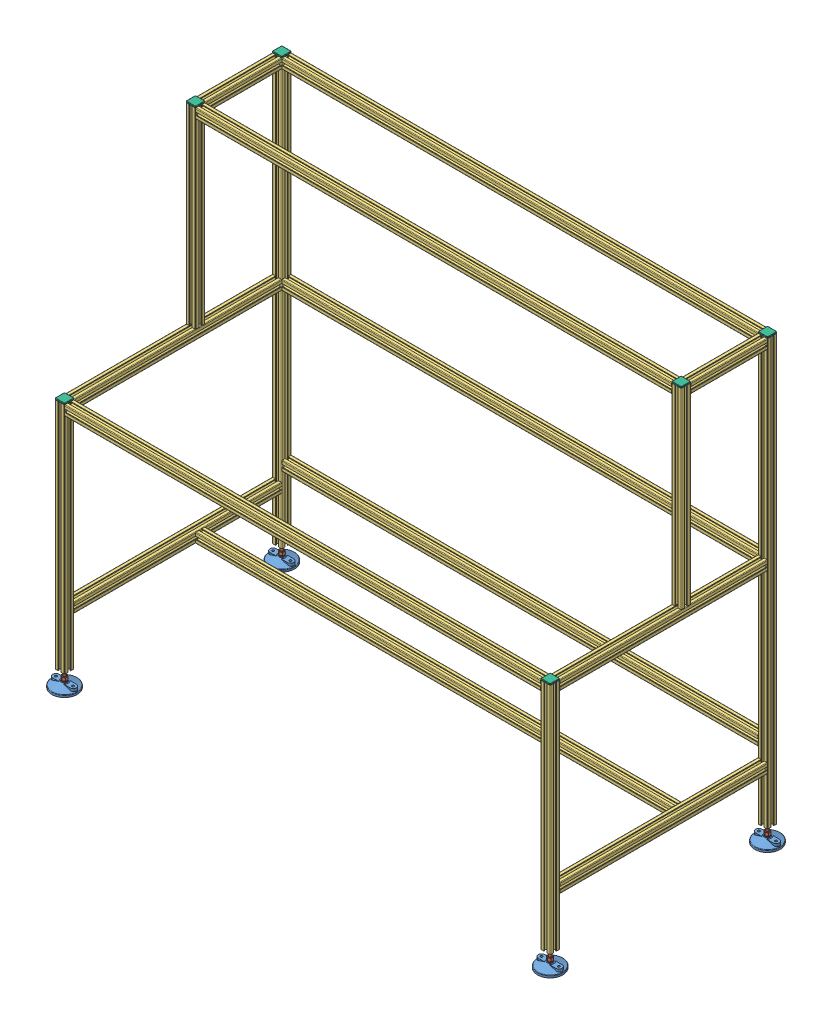
SolidWorks assembly AL-6 Рабочий стол большой с одной полкой сборка, configuration По умолчанию. Lengths in mm.
Overall size (1599 1384.2 759).
63 component instances, 6 part files, 70 mates.
Components (placement in the parent):
- AL-340.010BA.01 Опора D80 с противоскользящей вставкой-8: AL-340.010BA.01 Опора D80 с противоскользящей вставкой [Default] x (0 0 1) z (1 0 0) size (79 18 79)
- AL-1Y12.A42A.01 Шпилька к опоре М8х80-1: AL-1Y12.A42A.01 Шпилька к опоре М8х80 [Default] x (0.999247 0 0.038788) z (0.038788 0 -0.999247) size (15 105.5 18.13)
- AL-6-PS-3030.001 Профиль-2: AL-6-PS-3030.001 Профиль [Default] at (0 1315 255) size (30 30 240)
- AL-6-PS-3030.001 Профиль-36: AL-6-PS-3030.001 Профиль [-01] at (0 730 270) x (0 0 1) z (0 -1 0) size (30 30 600)
- AL-6-PS-3030.001 Профиль-6: AL-6-PS-3030.001 Профиль [Default] at (-1520 1315 255) size (30 30 240)
- AL-6-PS-3030.001 Профиль-38: AL-6-PS-3030.001 Профиль [-02] at (0 715 665) x (0 1 0) z (0 0 1) size (30 30 650)
- AL-6-PS-3030.001 Профиль-39: AL-6-PS-3030.001 Профиль [-02] at (-1520 715 665) x (0 1 0) z (0 0 1) size (30 30 650)
- AL-6-PS-3030.001 Профиль-40: AL-6-PS-3030.001 Профиль [-02] at (0 165 665) size (30 30 650)
- AL-6-PS-3030.001 Профиль-41: AL-6-PS-3030.001 Профиль [-02] at (-1520 165 665) size (30 30 650)
- AL-6-PS-3030.001 Профиль-42: AL-6-PS-3030.001 Профиль [-03] at (0 0 680) x (1 0 0) z (0 -1 0) size (30 30 730)
- AL-6-PS-3030.001 Профиль-43: AL-6-PS-3030.001 Профиль [-03] at (-1520 0 680) x (1 0 0) z (0 -1 0) size (30 30 730)
- AL-6-PS-3030.001 Профиль-44: AL-6-PS-3030.001 Профиль [-04] at (-1505 1315 270) x (0 0 1) z (-1 0 0) size (30 30 1490)
- AL-6-PS-3030.001 Профиль-45: AL-6-PS-3030.001 Профиль [-04] at (-1505 715 680) x (0 0 1) z (-1 0 0) size (30 30 1490)
- AL-6-PS-3030.001 Профиль-46: AL-6-PS-3030.001 Профиль [-04] at (-1505 715 0) x (0 0 1) z (-1 0 0) size (30 30 1490)
- AL-6-PS-3030.001 Профиль-47: AL-6-PS-3030.001 Профиль [-04] at (-1505 225 0) x (0 0 1) z (-1 0 0) size (30 30 1490)
- AL-6-PS-3030.001 Профиль-48: AL-6-PS-3030.001 Профиль [-04] at (-1505 1315 0) x (0 0 1) z (-1 0 0) size (30 30 1490)
- AL-6-PS-3030.001 Профиль-49: AL-6-PS-3030.001 Профиль [-04] at (-1505 165 270) x (0 0 1) z (-1 0 0) size (30 30 1490)
- AL-6-PS-3030.001 Профиль-50: AL-6-PS-3030.001 Профиль [-05] x (1 0 0) z (0 -1 0) size (30 30 1330)
- AL-6-PS-3030.001 Профиль-51: AL-6-PS-3030.001 Профиль [-05] at (-1520 0 0) x (1 0 0) z (0 -1 0) size (30 30 1330)
- AL-340.010BA.01 Опора D80 с противоскользящей вставкой-9: AL-340.010BA.01 Опора D80 с противоскользящей вставкой [Default] at (-1520 0 0) x (0 0 1) z (1 0 0) size (79 18 79)
- AL-340.010BA.01 Опора D80 с противоскользящей вставкой-10: AL-340.010BA.01 Опора D80 с противоскользящей вставкой [Default] at (0 0 680) x (0 0 1) z (1 0 0) size (79 18 79)
- AL-340.010BA.01 Опора D80 с противоскользящей вставкой-11: AL-340.010BA.01 Опора D80 с противоскользящей вставкой [Default] at (-1520 0 680) x (0 0 1) z (1 0 0) size (79 18 79)
- AL-1Y12.A42A.01 Шпилька к опоре М8х80-2: AL-1Y12.A42A.01 Шпилька к опоре М8х80 [Default] at (-1520 0 0) x (0.999247 0 0.038788) z (0.038788 0 -0.999247) size (15 105.5 18.13)
- AL-1Y12.A42A.01 Шпилька к опоре М8х80-3: AL-1Y12.A42A.01 Шпилька к опоре М8х80 [Default] at (0 0 680) x (0.999247 0 0.038788) z (0.038788 0 -0.999247) size (15 105.5 18.13)
- AL-1Y12.A42A.01 Шпилька к опоре М8х80-4: AL-1Y12.A42A.01 Шпилька к опоре М8х80 [Default] at (-1520 0 680) x (0.999247 0 0.038788) z (0.038788 0 -0.999247) size (15 105.5 18.13)
- AL-6-PS-3030.001 Профиль-37: AL-6-PS-3030.001 Профиль [-01] at (-1520 730 270) x (0 0 1) z (0 -1 0) size (30 30 600)
- hex nut gradec_din-1: hex nut gradec_din [Hexagon Nut ISO 4034 - M8 - N] at (0 -7.9 0) x (1 0 0) z (0 -1 0) size (13 15.01 7.9)
- hex nut gradec_din-2: hex nut gradec_din [Hexagon Nut ISO 4034 - M8 - N] at (-1520 -7.9 0) x (1 0 0) z (0 -1 0) size (13 15.01 7.9)
- hex nut gradec_din-3: hex nut gradec_din [Hexagon Nut ISO 4034 - M8 - N] at (0 -7.9 680) x (1 0 0) z (0 -1 0) size (13 15.01 7.9)
- hex nut gradec_din-4: hex nut gradec_din [Hexagon Nut ISO 4034 - M8 - N] at (-1520 -7.9 680) x (1 0 0) z (0 -1 0) size (13 15.01 7.9)
- socket button head screw_iso4-2: socket button head screw_iso4 [ISO 7380 - M8 x 25 - 25S] at (0 715 8.4) x (0 0 1) z (-1 0 0) size (29.4 14 14)
- socket button head screw_iso4-3: socket button head screw_iso4 [ISO 7380 - M8 x 25 - 25S] at (-8.4 1315 270) x (-1 0 0) z (0 -0.924225 -0.381849) size (29.4 14 14)
- socket button head screw_iso4-4: socket button head screw_iso4 [ISO 7380 - M8 x 25 - 25S] at (0 1315 261.6) x (0 0 -1) z (1 0 0) size (29.4 14 14)
- socket button head screw_iso4-5: socket button head screw_iso4 [ISO 7380 - M8 x 25 - 25S] at (-8.4 1315 0) x (-1 0 0) z (0 -0.924225 -0.381849) size (29.4 14 14)
- socket button head screw_iso4-6: socket button head screw_iso4 [ISO 7380 - M8 x 25 - 25S] at (0 1315 8.4) x (0 0 1) z (-1 0 0) size (29.4 14 14)
- socket button head screw_iso4-7: socket button head screw_iso4 [ISO 7380 - M8 x 25 - 25S] at (0 723.4 270) x (0 1 0) z (0 0 1) size (29.4 14 14)
- socket button head screw_iso4-8: socket button head screw_iso4 [ISO 7380 - M8 x 25 - 25S] at (-8.4 715 0) x (-1 0 0) z (0 0 -1) size (29.4 14 14)
- socket button head screw_iso4-9: socket button head screw_iso4 [ISO 7380 - M8 x 25 - 25S] at (-8.4 225 0) x (-1 0 0) z (0 0.005268 -0.999986) size (29.4 14 14)
- socket button head screw_iso4-10: socket button head screw_iso4 [ISO 7380 - M8 x 25 - 25S] at (0 165 8.4) x (0 0 1) z (-0.999986 0.005268 0) size (29.4 14 14)
- socket button head screw_iso4-11: socket button head screw_iso4 [ISO 7380 - M8 x 25 - 25S] at (-8.4 165 270) x (-1 0 0) z (0 0.005268 -0.999986) size (29.4 14 14)
- socket button head screw_iso4-12: socket button head screw_iso4 [ISO 7380 - M8 x 25 - 25S] at (0 165 671.6) x (0 0 -1) z (0.999986 0.005268 0) size (29.4 14 14)
- socket button head screw_iso4-13: socket button head screw_iso4 [ISO 7380 - M8 x 25 - 25S] at (-8.4 715 680) x (-1 0 0) z (0 0.005268 -0.999986) size (29.4 14 14)
- socket button head screw_iso4-14: socket button head screw_iso4 [ISO 7380 - M8 x 25 - 25S] at (0 715 671.6) x (0 0 -1) z (0.999986 0.005268 0) size (29.4 14 14)
- AL-375.0200A.01 Заглушка торцевая 30х30-34: AL-375.0200A.01 Заглушка торцевая 30х30 [По умолчанию] at (-15 734.2 665) x (1 0 0) z (0 -1 0) size (30 30 9.2)
- AL-375.0200A.01 Заглушка торцевая 30х30-35: AL-375.0200A.01 Заглушка торцевая 30х30 [По умолчанию] at (-15 1334.2 255) x (1 0 0) z (0 -1 0) size (30 30 9.2)
- AL-375.0200A.01 Заглушка торцевая 30х30-36: AL-375.0200A.01 Заглушка торцевая 30х30 [По умолчанию] at (-15 1334.2 -15) x (1 0 0) z (0 -1 0) size (30 30 9.2)
- hex nut gradec_din-5: hex nut gradec_din [Hexagon Nut ISO 4034 - M8 - N] at (-1520 0 0) x (-1 0 0) z (0 1 0) size (13 15.01 7.9)
- AL-375.0200A.01 Заглушка торцевая 30х30-37: AL-375.0200A.01 Заглушка торцевая 30х30 [По умолчанию] at (-1535 1334.2 -15) x (1 0 0) z (0 -1 0) size (30 30 9.2)
- AL-375.0200A.01 Заглушка торцевая 30х30-38: AL-375.0200A.01 Заглушка торцевая 30х30 [По умолчанию] at (-1535 1334.2 255) x (1 0 0) z (0 -1 0) size (30 30 9.2)
- AL-375.0200A.01 Заглушка торцевая 30х30-39: AL-375.0200A.01 Заглушка торцевая 30х30 [По умолчанию] at (-1535 734.2 665) x (1 0 0) z (0 -1 0) size (30 30 9.2)
- socket button head screw_iso4-15: socket button head screw_iso4 [ISO 7380 - M8 x 25 - 25S] at (-1520 715 671.6) x (0 0 -1) z (0.999986 -0.005268 0) size (29.4 14 14)
- socket button head screw_iso4-16: socket button head screw_iso4 [ISO 7380 - M8 x 25 - 25S] at (-1511.6 715 680) x (1 0 0) z (0 -0.005268 0.999986) size (29.4 14 14)
- socket button head screw_iso4-17: socket button head screw_iso4 [ISO 7380 - M8 x 25 - 25S] at (-1520 165 671.6) x (0 0 -1) z (0.999986 -0.005268 0) size (29.4 14 14)
- socket button head screw_iso4-18: socket button head screw_iso4 [ISO 7380 - M8 x 25 - 25S] at (-1511.6 165 270) x (1 0 0) z (0 -0.005268 0.999986) size (29.4 14 14)
- socket button head screw_iso4-19: socket button head screw_iso4 [ISO 7380 - M8 x 25 - 25S] at (-1520 165 8.4) x (0 0 1) z (-0.999986 -0.005268 0) size (29.4 14 14)
- socket button head screw_iso4-20: socket button head screw_iso4 [ISO 7380 - M8 x 25 - 25S] at (-1511.6 225 0) x (1 0 0) z (0 -0.005268 0.999986) size (29.4 14 14)
- socket button head screw_iso4-21: socket button head screw_iso4 [ISO 7380 - M8 x 25 - 25S] at (-1511.6 715 0) size (29.4 14 14)
- socket button head screw_iso4-22: socket button head screw_iso4 [ISO 7380 - M8 x 25 - 25S] at (-1520 723.4 270) x (0 1 0) z (0 0 -1) size (29.4 14 14)
- socket button head screw_iso4-23: socket button head screw_iso4 [ISO 7380 - M8 x 25 - 25S] at (-1520 1315 8.4) x (0 0 1) z (-1 0 0) size (29.4 14 14)
- socket button head screw_iso4-24: socket button head screw_iso4 [ISO 7380 - M8 x 25 - 25S] at (-1511.6 1315 0) x (1 0 0) z (0 0.924225 0.381849) size (29.4 14 14)
- socket button head screw_iso4-25: socket button head screw_iso4 [ISO 7380 - M8 x 25 - 25S] at (-1520 1315 261.6) x (0 0 -1) z (1 0 0) size (29.4 14 14)
- socket button head screw_iso4-26: socket button head screw_iso4 [ISO 7380 - M8 x 25 - 25S] at (-1511.6 1315 270) x (1 0 0) z (0 0.924225 0.381849) size (29.4 14 14)
- socket button head screw_iso4-27: socket button head screw_iso4 [ISO 7380 - M8 x 25 - 25S] at (-1520 715 8.4) x (0 0 1) z (-1 0 0) size (29.4 14 14)
Mates (geometry in assembly coordinates):
- Совпадение1: coincident aligned: plane of AL-6-PS-3030.001 Профиль-50 through (0 0 0) normal (0 0 1)
- Совпадение2: coincident anti-aligned: plane of AL-6-PS-3030.001 Профиль-50 through (0 0 0) normal (0 -1 0)
- Совпадение3: coincident aligned: plane of AL-6-PS-3030.001 Профиль-50 through (0 0 0) normal (1 0 0)
- Совпадение4: coincident aligned: plane of AL-6-PS-3030.001 Профиль-50 through (15 1330 13) normal (1 0 0); plane of AL-6-PS-3030.001 Профиль-2 through (15 1328 15) normal (1 0 0)
- Совпадение5: coincident anti-aligned: plane of AL-6-PS-3030.001 Профиль-50 through (4.75 1330 15) normal (0 0 1); plane of AL-6-PS-3030.001 Профиль-2 through (-8.05 1302.4 15) normal (0 0 -1)
- Совпадение6: coincident aligned: plane of AL-6-PS-3030.001 Профиль-50 through (-8.05 1330 -12.6) normal (0 1 0); plane of AL-6-PS-3030.001 Профиль-2 through (-4.75 1330 15) normal (0 1 0)
- Совпадение7: coincident aligned: plane of AL-6-PS-3030.001 Профиль-50 through (15 1330 13) normal (1 0 0); plane of AL-6-PS-3030.001 Профиль-42 through (15 730 667) normal (1 0 0)
- Совпадение8: coincident aligned: plane of AL-6-PS-3030.001 Профиль-50 through (-8.05 0 -12.6) normal (0 -1 0); plane of AL-6-PS-3030.001 Профиль-42 through (-8.05 0 667.4) normal (0 -1 0)
- Совпадение11: coincident anti-aligned: plane of AL-6-PS-3030.001 Профиль-42 through (4.75 730 665) normal (0 0 -1); plane of AL-6-PS-3030.001 Профиль-38 through (12.6 706.95 665) normal (0 0 1)
- Совпадение12: coincident anti-aligned: plane of AL-6-PS-3030.001 Профиль-50 through (4.75 1330 15) normal (0 0 1); plane of AL-6-PS-3030.001 Профиль-38 through (12.6 706.95 15) normal (0 0 -1)
- Расстояние1: distance = 150 mm aligned: plane of AL-6-PS-3030.001 Профиль-40 through (4.75 150 15) normal (0 -1 0); plane of AL-6-PS-3030.001 Профиль-42 through (-8.05 0 667.4) normal (0 -1 0)
- Совпадение15: coincident anti-aligned: plane of AL-6-PS-3030.001 Профиль-42 through (4.75 730 665) normal (0 0 -1); plane of AL-6-PS-3030.001 Профиль-40 through (-8.05 152.4 665) normal (0 0 1)
- Совпадение16: coincident aligned: plane of AL-6-PS-3030.001 Профиль-42 through (-8.05 730 667.4) normal (0 1 0); plane of AL-6-PS-3030.001 Профиль-45 through (-15 730 684.75) normal (0 1 0)
- Совпадение17: coincident aligned: plane of AL-6-PS-3030.001 Профиль-42 through (-4.75 730 695) normal (0 0 1); plane of AL-6-PS-3030.001 Профиль-45 through (-15 728 695) normal (0 0 1)
- Совпадение18: coincident anti-aligned: plane of AL-6-PS-3030.001 Профиль-42 through (-15 730 693) normal (-1 0 0); plane of AL-6-PS-3030.001 Профиль-45 through (-15 702.4 671.95) normal (1 0 0)
- Совпадение19: coincident aligned: plane of AL-6-PS-3030.001 Профиль-45 through (-15 730 684.75) normal (0 1 0); plane of AL-6-PS-3030.001 Профиль-46 through (-15 730 4.75) normal (0 1 0)
- Совпадение20: coincident aligned: plane of AL-6-PS-3030.001 Профиль-51 through (-1515.25 1330 -15) normal (0 0 -1); plane of AL-6-PS-3030.001 Профиль-46 through (-15 728 -15) normal (0 0 -1)
- Совпадение21: coincident aligned: plane of AL-6-PS-3030.001 Профиль-45 through (-1505 702.4 671.95) normal (-1 0 0); plane of AL-6-PS-3030.001 Профиль-46 through (-1505 702.4 -8.05) normal (-1 0 0)
- Совпадение22: coincident aligned: plane of AL-6-PS-3030.001 Профиль-40 through (4.75 180 15) normal (0 1 0); plane of AL-6-PS-3030.001 Профиль-49 through (-15 180 274.75) normal (0 1 0)
- Совпадение23: coincident anti-aligned: plane of AL-6-PS-3030.001 Профиль-40 through (-15 152 15) normal (-1 0 0); plane of AL-6-PS-3030.001 Профиль-49 through (-15 152.4 261.95) normal (1 0 0)
- Расстояние2: distance = 240 mm anti-aligned: plane of AL-6-PS-3030.001 Профиль-49 through (-15 178 255) normal (0 0 -1); plane of AL-6-PS-3030.001 Профиль-50 through (-4.75 1330 15) normal (0 0 1)
- Совпадение26: coincident anti-aligned: plane of AL-6-PS-3030.001 Профиль-2 through (-15 1328 15) normal (-1 0 0); plane of AL-6-PS-3030.001 Профиль-44 through (-15 1302.4 261.95) normal (1 0 0)
- Совпадение27: coincident aligned: plane of AL-6-PS-3030.001 Профиль-2 through (-4.75 1330 15) normal (0 1 0); plane of AL-6-PS-3030.001 Профиль-44 through (-15 1330 274.75) normal (0 1 0)
- Концентричный2: concentric anti-aligned: cylinder of AL-1Y12.A42A.01 Шпилька к опоре М8х80-1 through (0 -18 0) axis (0 1 0) radius 4; cylinder of AL-340.010BA.01 Опора D80 с противоскользящей вставкой-8 through (0 0 0) axis (0 -1 0) radius 39.5
- Концентричный272: concentric anti-aligned: cylinder of AL-6-PS-3030.001 Профиль-50 through (0 1330 0) axis (0 -1 0) radius 3.65; cylinder of AL-1Y12.A42A.01 Шпилька к опоре М8х80-1 through (0 -18 0) axis (0 1 0) radius 4
- Совпадение563: coincident aligned: plane of AL-6-PS-3030.001 Профиль-38 through (-13 730 15) normal (0 1 0); plane of AL-6-PS-3030.001 Профиль-42 through (-8.05 730 667.4) normal (0 1 0)
- Совпадение564: coincident aligned: plane of AL-6-PS-3030.001 Профиль-38 through (15 719.75 15) normal (1 0 0); plane of AL-6-PS-3030.001 Профиль-42 through (15 730 667) normal (1 0 0)
- Совпадение565: coincident aligned: plane of AL-6-PS-3030.001 Профиль-38 through (15 719.75 15) normal (1 0 0); plane of AL-6-PS-3030.001 Профиль-40 through (15 178 15) normal (1 0 0)
- Расстояние4: distance = 300 mm anti-aligned: plane of AL-6-PS-3030.001 Профиль-44 through (-15 1328 285) normal (0 0 1); plane of AL-6-PS-3030.001 Профиль-48 through (-15 1328 -15) normal (0 0 -1)
- Совпадение567: coincident anti-aligned: plane of AL-6-PS-3030.001 Профиль-2 through (-8.05 1302.4 255) normal (0 0 1); plane of AL-6-PS-3030.001 Профиль-36 through (-13 1330 255) normal (0 0 -1)
- Совпадение568: coincident anti-aligned: plane of AL-6-PS-3030.001 Профиль-36 through (-15 1330 274.75) normal (-1 0 0); plane of AL-6-PS-3030.001 Профиль-44 through (-15 1302.4 261.95) normal (1 0 0)
- Совпадение569: coincident aligned: plane of AL-6-PS-3030.001 Профиль-36 through (12.6 1330 261.95) normal (0 1 0); plane of AL-6-PS-3030.001 Профиль-44 through (-15 1330 274.75) normal (0 1 0)
- Концентричный273: concentric anti-aligned: cylinder of AL-1Y12.A42A.01 Шпилька к опоре М8х80-1 through (0 -18 0) axis (0 1 0) radius 4; cylinder of hex nut gradec_din-1 through (0 0 0) axis (0 -1 0) radius 3.4
- Совпадение570: coincident: line of AL-6-PS-3030.001 Профиль-50 through (6.0045 0 -4.2045) axis (0 0 1); plane of hex nut gradec_din-1 through (-13 0 0) normal (0 1 0)
- Совпадение571: coincident anti-aligned: plane of AL-6-PS-3030.001 Профиль-36 through (-12.8 1330 265.35) normal (1 0 0); plane of socket button head screw_iso-3 through (-12.8 1316.5274 266.3031) normal (-1 0 0)
- Совпадение572: coincident anti-aligned: plane of AL-6-PS-3030.001 Профиль-36 through (8.05 1330 257.2) normal (0 0 1); plane of socket button head screw_iso-4 through (0 1319 257.2) normal (0 0 -1)
- Совпадение573: coincident anti-aligned: plane of AL-6-PS-3030.001 Профиль-50 through (-12.8 1330 8.05) normal (1 0 0); plane of socket button head screw_iso-5 through (-12.8 1316.5274 -3.6969) normal (-1 0 0)
- Совпадение574: coincident anti-aligned: plane of AL-6-PS-3030.001 Профиль-50 through (-4.65 1330 12.8) normal (0 0 -1); plane of socket button head screw_iso-6 through (0 1319 12.8) normal (0 0 1)
- Концентричный274: concentric anti-aligned: cylinder of AL-6-PS-3030.001 Профиль-44 through (-15 1315 270) axis (-1 0 0) radius 3.65; circle of socket button head screw_iso-3
- Концентричный275: concentric aligned: cylinder of AL-6-PS-3030.001 Профиль-2 through (0 1315 15) axis (0 0 1) radius 3.65; cylinder of socket button head screw_iso-4 through (0 1315 261.6) axis (0 0 1) radius 4
- Совпадение575: coincident anti-aligned: plane of AL-6-PS-3030.001 Профиль-38 through (-8.05 727.8 15) normal (0 -1 0); plane of socket button head screw_iso-7 through (-4 727.8 270) normal (0 1 0)
- Концентричный276: concentric aligned: cylinder of AL-6-PS-3030.001 Профиль-36 through (0 1330 270) axis (0 -1 0) radius 3.65; circle of socket button head screw_iso-7
- Совпадение576: coincident anti-aligned: plane of AL-6-PS-3030.001 Профиль-50 through (-12.8 1330 -8.05) normal (1 0 0); plane of socket button head screw_iso-5 through (-12.8 1316.5274 -3.6969) normal (-1 0 0)
- Концентричный277: concentric anti-aligned: cylinder of AL-6-PS-3030.001 Профиль-48 through (-15 1315 0) axis (-1 0 0) radius 3.65; circle of socket button head screw_iso-5
- Концентричный278: concentric anti-aligned: cylinder of AL-6-PS-3030.001 Профиль-2 through (0 1315 15) axis (0 0 1) radius 3.65; circle of socket button head screw_iso-6
- Совпадение577: coincident anti-aligned: plane of AL-6-PS-3030.001 Профиль-50 through (-4.65 1330 12.8) normal (0 0 -1); plane of socket button head screw_iso-2 through (0 719 12.8) normal (0 0 1)
- Концентричный279: concentric anti-aligned: cylinder of AL-6-PS-3030.001 Профиль-38 through (0 715 15) axis (0 0 1) radius 3.65; circle of socket button head screw_iso-2
- Совпадение578: coincident anti-aligned: plane of AL-6-PS-3030.001 Профиль-50 through (-12.8 1330 -8.05) normal (1 0 0); plane of socket button head screw_iso-8 through (-12.8 719 0) normal (-1 0 0)
- Концентричный280: concentric anti-aligned: cylinder of AL-6-PS-3030.001 Профиль-46 through (-15 715 0) axis (-1 0 0) radius 3.65; cylinder of socket button head screw_iso-8 through (-8.4 715 0) axis (1 0 0) radius 4
- Совпадение579: coincident anti-aligned: plane of AL-6-PS-3030.001 Профиль-50 through (-12.8 1330 8.05) normal (1 0 0); plane of socket button head screw_iso-9 through (-12.8 228.9999 0.0211) normal (-1 0 0)
- Концентричный281: concentric anti-aligned: cylinder of AL-6-PS-3030.001 Профиль-47 through (-15 225 0) axis (-1 0 0) radius 3.65; circle of socket button head screw_iso-9
- Совпадение580: coincident anti-aligned: plane of AL-6-PS-3030.001 Профиль-50 through (4.65 1330 12.8) normal (0 0 -1); plane of socket button head screw_iso-10 through (0.0211 168.9999 12.8) normal (0 0 1)
- Концентричный282: concentric anti-aligned: cylinder of AL-6-PS-3030.001 Профиль-40 through (0 165 15) axis (0 0 1) radius 3.65; circle of socket button head screw_iso-10
- Совпадение581: coincident anti-aligned: plane of AL-6-PS-3030.001 Профиль-40 through (-12.8 173.05 15) normal (1 0 0); plane of socket button head screw_iso-11 through (-12.8 168.9999 270.0211) normal (-1 0 0)
- Концентричный283: concentric anti-aligned: cylinder of AL-6-PS-3030.001 Профиль-49 through (-15 165 270) axis (-1 0 0) radius 3.65; cylinder of socket button head screw_iso-11 through (-8.4 165 270) axis (1 0 0) radius 7
- Совпадение582: coincident anti-aligned: plane of AL-6-PS-3030.001 Профиль-42 through (4.65 730 667.2) normal (0 0 1); plane of socket button head screw_iso-12 through (-0.0211 168.9999 667.2) normal (0 0 -1)
- Концентричный284: concentric aligned: cylinder of AL-6-PS-3030.001 Профиль-40 through (0 165 15) axis (0 0 1) radius 3.65; cylinder of socket button head screw_iso-12 through (0 165 671.6) axis (0 0 1) radius 4
- Совпадение583: coincident anti-aligned: plane of AL-6-PS-3030.001 Профиль-42 through (-12.8 730 671.95) normal (1 0 0); plane of socket button head screw_iso-13 through (-12.8 718.9999 680.0211) normal (-1 0 0)
- Концентричный285: concentric anti-aligned: cylinder of AL-6-PS-3030.001 Профиль-45 through (-15 715 680) axis (-1 0 0) radius 3.65; circle of socket button head screw_iso-13
- Совпадение584: coincident anti-aligned: plane of AL-6-PS-3030.001 Профиль-42 through (4.65 730 667.2) normal (0 0 1); plane of socket button head screw_iso-14 through (-0.0211 718.9999 667.2) normal (0 0 -1)
- Концентричный286: concentric aligned: cylinder of AL-6-PS-3030.001 Профиль-38 through (0 715 15) axis (0 0 1) radius 3.65; cylinder of socket button head screw_iso-14 through (0 715 671.6) axis (0 0 1) radius 7
- Совпадение585: coincident anti-aligned: plane of AL-6-PS-3030.001 Профиль-42 through (-8.05 730 667.4) normal (0 1 0); plane of AL-375.0200A.01 Заглушка торцевая 30х30-34 through (3.6986 730 695) normal (0 -1 0)
- Совпадение586: coincident aligned: plane of AL-6-PS-3030.001 Профиль-42 through (4.75 730 695) normal (0 0 1); plane of AL-375.0200A.01 Заглушка торцевая 30х30-34 through (-15 734.2 695) normal (0 0 1)
- Совпадение587: coincident aligned: plane of AL-6-PS-3030.001 Профиль-42 through (15 730 693) normal (1 0 0); plane of AL-375.0200A.01 Заглушка торцевая 30х30-34 through (15 734.2 665) normal (1 0 0)
- Совпадение588: coincident anti-aligned: plane of AL-6-PS-3030.001 Профиль-36 through (12.6 1330 261.95) normal (0 1 0); plane of AL-375.0200A.01 Заглушка торцевая 30х30-35 through (3.6986 1330 285) normal (0 -1 0)
- Совпадение589: coincident aligned: plane of AL-6-PS-3030.001 Профиль-36 through (13 1330 285) normal (0 0 1); plane of AL-375.0200A.01 Заглушка торцевая 30х30-35 through (-15 1334.2 285) normal (0 0 1)
- Совпадение590: coincident aligned: plane of AL-6-PS-3030.001 Профиль-36 through (15 1330 274.75) normal (1 0 0); plane of AL-375.0200A.01 Заглушка торцевая 30х30-35 through (15 1334.2 255) normal (1 0 0)
- Совпадение591: coincident anti-aligned: plane of AL-6-PS-3030.001 Профиль-50 through (-8.05 1330 -12.6) normal (0 1 0); plane of AL-375.0200A.01 Заглушка торцевая 30х30-36 through (3.6986 1330 15) normal (0 -1 0)
- Совпадение592: coincident aligned: plane of AL-6-PS-3030.001 Профиль-50 through (15 1330 13) normal (1 0 0); plane of AL-375.0200A.01 Заглушка торцевая 30х30-36 through (15 1334.2 -15) normal (1 0 0)
- Совпадение593: coincident aligned: plane of AL-6-PS-3030.001 Профиль-50 through (4.75 1330 -15) normal (0 0 -1); plane of AL-375.0200A.01 Заглушка торцевая 30х30-36 through (-15 1334.2 -15) normal (0 0 -1)
